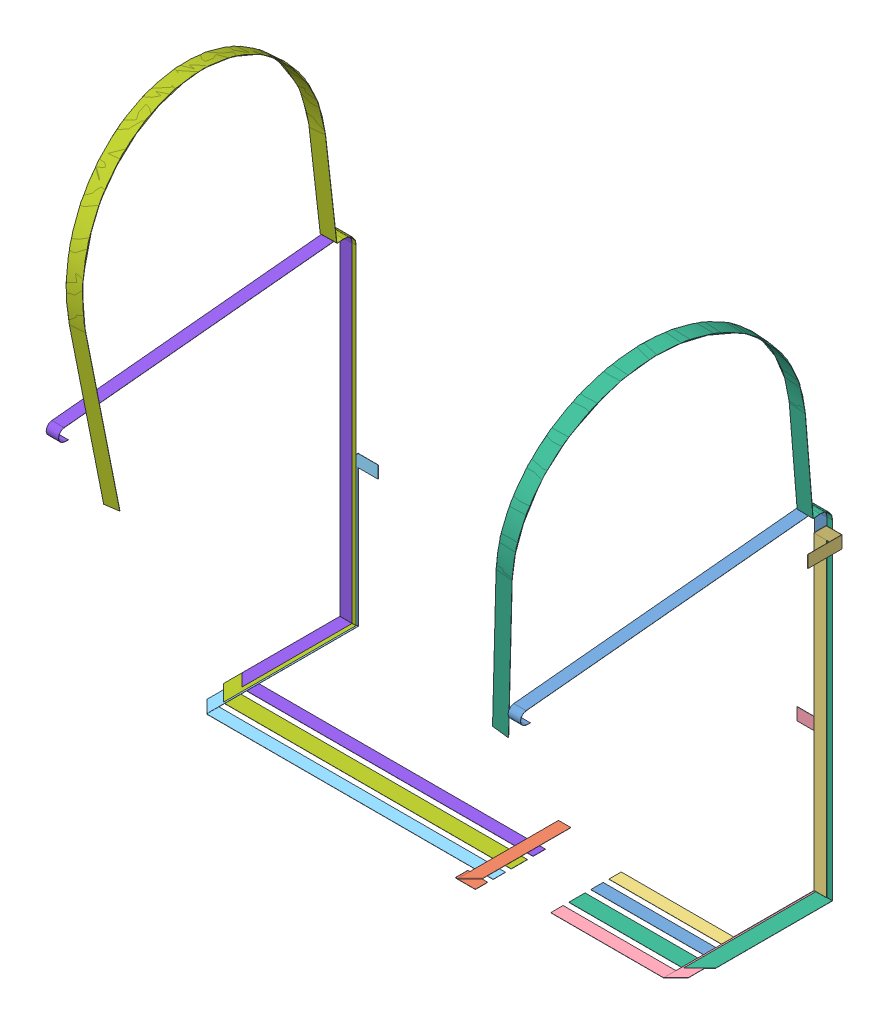
SolidWorks assembly 040M09C00.0P000 Wiring, configuration Default. Lengths in mm.
Overall size (666.76 729.48 399.53).
8 component instances, 8 part files, 52 mates.
Components (placement in the parent):
- 040M09C00.0P01A FFC X1 stepper-1: 040M09C00.0P01A FFC X1 stepper [Right] at (150 -28.8609 147.9733) size (163.25 443.39 398.73)
- 040M09C00.0P03A FFC Z stepper-1: 040M09C00.0P03A FFC Z stepper [Right] at (75 -28.8609 206.9733) x (0 0 1) z (-1 0 0) size (130.9 1.15 26)
- 040M09C00.0P04A FFC Y stepper-1: 040M09C00.0P04A FFC Y stepper [Right] at (150 -28.8609 108.4733) x (0 0 1) z (0 -1 0) size (120.43 183.17 419.7)
- 040M09C00.0P05A FFC Extruder 1-1: 040M09C00.0P05A FFC Extruder 1 [Right] at (150 -28.8609 199.9733) size (163.25 195.95 197.23)
- 040M09C00.0P06B FFC Extruder 0-1: 040M09C00.0P06B FFC Extruder 0 [Left] at (75 -28.8609 199.9733) size (388.25 195.7 197.23)
- 040M09C00.0P08B FFC Hotend 1-1: 040M09C00.0P08B FFC Hotend 1 [Right] at (150 -28.8609 176.4733) size (183.38 729.33 385.22)
- 040M09C00.0P07C FFC Hotend 0-1: 040M09C00.0P07C FFC Hotend 0 [Left] at (75 -28.8609 176.4733) size (408.38 729.48 385.43)
- 040M09C00.0P02B FFC X0 stepper-2: 040M09C00.0P02B FFC X0 stepper [Left] at (75 -28.8609 147.9733) size (395.25 443.39 381.94)
Mates (geometry in assembly coordinates):
- Coincident1: coincident aligned: plane of 040M09C00.0P01A FFC X1 stepper-1 through (150 -29.1109 147.9733) normal (0 -1 0); plane of 040M09C00.0P04A FFC Y stepper-1 through (150 -29.1109 108.4733) normal (0 -1 0)
- Coincident2: coincident aligned: plane of 040M09C00.0P01A FFC X1 stepper-1 through (150 -29.1109 147.9733) normal (0 -1 0); plane of 040M09C00.0P07C FFC Hotend 0-1 through (75 -29.1109 176.4733) normal (0 -1 0)
- Coincident3: coincident aligned: plane of 040M09C00.0P01A FFC X1 stepper-1 through (150 -29.1109 147.9733) normal (0 -1 0); plane of 040M09C00.0P08B FFC Hotend 1-1 through (150 -29.1109 176.4733) normal (0 -1 0)
- Coincident4: coincident aligned: plane of 040M09C00.0P01A FFC X1 stepper-1 through (150 -29.1109 147.9733) normal (0 -1 0); plane of 040M09C00.0P05A FFC Extruder 1-1 through (150 -29.1109 199.9733) normal (0 -1 0)
- Coincident5: coincident aligned: plane of 040M09C00.0P01A FFC X1 stepper-1 through (150 -29.1109 147.9733) normal (0 -1 0); plane of 040M09C00.0P06B FFC Extruder 0-1 through (75 -29.1109 199.9733) normal (0 -1 0)
- Coincident6: coincident aligned: plane of 040M09C00.0P01A FFC X1 stepper-1 through (150 -29.1109 147.9733) normal (0 -1 0); plane of ? through (77.425 3 147.9733) normal (0 -1 0)
- Coincident8: coincident aligned: plane of 040M09C00.0P01A FFC X1 stepper-1 through (150 -29.1109 147.9733) normal (-1 0 0); plane of 040M09C00.0P04A FFC Y stepper-1 through (150 -29.1109 108.4733) normal (-1 0 0)
- Coincident9: coincident aligned: plane of 040M09C00.0P01A FFC X1 stepper-1 through (150 -29.1109 147.9733) normal (-1 0 0); plane of 040M09C00.0P08B FFC Hotend 1-1 through (150 -29.1109 176.4733) normal (-1 0 0)
- Coincident10: coincident aligned: plane of 040M09C00.0P04A FFC Y stepper-1 through (150 -29.1109 108.4733) normal (-1 0 0); plane of 040M09C00.0P05A FFC Extruder 1-1 through (150 -29.1109 199.9733) normal (-1 0 0)
- Coincident11: coincident aligned: plane of 040M09C00.0P06B FFC Extruder 0-1 through (75 -29.1109 199.9733) normal (1 0 0); plane of 040M09C00.0P07C FFC Hotend 0-1 through (75 -29.1109 176.4733) normal (1 0 0)
- Distance2: distance = 75 mm: line of 040M09C00.0P07C FFC Hotend 0-1 through (75 -28.8609 176.4733) axis (0 0 -1); line of 040M09C00.0P08B FFC Hotend 1-1 through (150 -28.8609 155.4733) axis (0 0 1)
- Distance4: distance = 7.5 mm anti-aligned: plane of 040M09C00.0P07C FFC Hotend 0-1 through (-1810 -29.1109 176.4733) normal (0 0 1); plane of 040M09C00.0P06B FFC Extruder 0-1 through (-715 -29.1109 183.9733) normal (0 0 -1)
- Distance5: distance = 7.5 mm anti-aligned: plane of 040M09C00.0P07C FFC Hotend 0-1 through (-1810 -29.1109 155.4733) normal (0 0 -1); plane of ? through (-1268.575 3 147.9733) normal (0 0 1)
- Coincident12: coincident: plane of ? through (77.425 3 147.9733) normal (1 0 0); plane of 040M09C00.0P06B FFC Extruder 0-1 through (75 -29.1109 199.9733) normal (1 0 0)
- Distance6: distance = 7.5 mm anti-aligned: plane of 040M09C00.0P08B FFC Hotend 1-1 through (150 -29.1109 176.4733) normal (0 0 1); plane of 040M09C00.0P05A FFC Extruder 1-1 through (150 -29.1109 183.9733) normal (0 0 -1)
- Distance7: distance = 7.5 mm anti-aligned: plane of 040M09C00.0P08B FFC Hotend 1-1 through (150 -29.1109 155.4733) normal (0 0 -1); plane of 040M09C00.0P01A FFC X1 stepper-1 through (150 -29.1109 147.9733) normal (0 0 1)
- Distance8: distance = 7.5 mm anti-aligned: plane of 040M09C00.0P04A FFC Y stepper-1 through (150 -29.1109 124.4733) normal (0 0 1); plane of 040M09C00.0P01A FFC X1 stepper-1 through (150 -29.1109 131.9733) normal (0 0 -1)
- Coincident20: coincident aligned: plane of 040M09C00.0P07C FFC Hotend 0-1 through (-1810 -29.1109 176.4733) normal (0 0 1); plane of 040M09C00.0P08B FFC Hotend 1-1 through (150 -29.1109 176.4733) normal (0 0 1)
- Distancia1: distance = 3 mm: plane of assembly through (0 0 0) normal (0 0 1); plane of ? through (-286.5 -542.8767 3) normal (0 0 -1)
- Distancia2: distance = 3 mm: plane of ? through (87.5 3 175.6733) normal (0 -1 0); plane of assembly through (0 0 0) normal (0 1 0)
- Distancia3: distance = 307.5 mm: plane of ? through (-307.5 364.6391 857.5836) normal (-1 0 0); plane of assembly through (0 0 0) normal (1 0 0)
- Distancia4: distance = 0.1 mm anti-aligned: plane of 040M09C00.0P02B FFC X0 stepper-2 through (-304 -28.6609 526.9733) normal (0 -1 0); plane of ? through (-286.5 3.7 324.6733) normal (0 1 0)
- Distancia5: distance = 0.1 mm: plane of ? through (-286.5 -317.8767 3.25) normal (0 0 1); plane of 040M09C00.0P02B FFC X0 stepper-2 through (-304 -551.4876 3.8) normal (0 0 -1)
- Coincidente6: coincident: plane of ? through (-137.5 3 175.6733) normal (1 0 0); plane of 040M09C00.0P02B FFC X0 stepper-2 through (75 -29.1109 147.9733) normal (1 0 0)
- Distancia6: distance = 0.1 mm: plane of ? through (-480.5 4.15 543.6733) normal (0 -1 0); plane of 040M09C00.0P02B FFC X0 stepper-2 through (-304 -28.4109 526.9733) normal (0 1 0)
- Distancia7: distance = 0.1 mm anti-aligned: plane of 040M09C00.0P02B FFC X0 stepper-2 through (-304 -551.4876 4.05) normal (0 0 1); plane of ? through (-480.5 -535.4767 3.7) normal (0 0 -1)
- Coincidente9: coincident: plane of ? through (87.5 3.7 200.6733) normal (1 0 0); plane of ? through (87.5 3 175.6733) normal (1 0 0)
- Simétrico1: symmetric: plane of ? through (-300.5 4.4 -217.3267) normal (-1 0 0); plane of ? through (300.5 4.4 347.6733) normal (1 0 0)
- Coincidente10: coincident: plane of ? through (-286.5 -542.8767 3) normal (0 0 -1); plane of ? through (286.5 -317.8767 3) normal (0 0 -1)
- Coincidente11: coincident: plane of ? through (-286.5 3.45 549.6733) normal (0 -1 0); plane of ? through (286.5 3.45 324.6733) normal (0 -1 0)
- Coincidente12: coincident: plane of ? through (87.5 3.7 200.6733) normal (0 -1 0); plane of ? through (137.5 3.7 200.6733) normal (0 -1 0)
- Coincidente13: coincident: plane of ? through (-1048.1267 199.15 4.15) normal (0 0 -1); plane of ? through (823.3767 199.4 4.15) normal (0 0 -1)
- Coincidente14: coincident aligned: plane of 040M09C00.0P02B FFC X0 stepper-2 through (75 -29.1109 147.9733) normal (0 -1 0); plane of ? through (333.5 3.35 147.5233) normal (0 -1 0)
- Coincidente16: coincident aligned: plane of 040M09C00.0P02B FFC X0 stepper-2 through (-1290 -29.1109 131.9733) normal (0 0 -1); plane of ? through (333.5 3.35 131.5233) normal (0 0 -1)
- Distancia8: distance = 0.1 mm: plane of ? through (300 -261.8267 3.7) normal (0 0 -1); plane of ? through (284.5 -287.0267 3.6) normal (0 0 1)
- Distancia9: distance = 0.1 mm: plane of ? through (300 4.5 270.3733) normal (0 -1 0); plane of ? through (284.5 4.4 347.6733) normal (0 1 0)
- Coincidente19: coincident: plane of ? through (137.5 3 175.6733) normal (-1 0 0); plane of ? through (137.5 3.7 200.6733) normal (-1 0 0)
- Coincidente20: coincident: plane of ? through (137.5 3 175.6733) normal (-1 0 0); plane of ? through (137.5 3.35 147.5233) normal (-1 0 0)
- Coincidente21: coincident: plane of ? through (137.5 3.35 147.5233) normal (-1 0 0); plane of ? through (137.5 4.05 107.8733) normal (-1 0 0)
- Distancia10: distance = 0.1 mm: plane of ? through (-284.5 4.4 572.6733) normal (0 1 0); plane of ? through (87.5 4.5 208.1733) normal (0 -1 0)
- Coincidente23: coincident: plane of ? through (87.5 3.7 200.6733) normal (1 0 0); plane of ? through (87.5 4.75 208.1733) normal (1 0 0)
- Distancia11: distance = 23.5 mm: plane of ? through (-702.5 3.7 200.6733) normal (0 0 1); plane of ? through (87.5 4.75 224.1733) normal (0 0 1)
- Distancia12: distance = 3 mm: plane of assembly through (0 0 0) normal (0 1 0); plane of ? through (77.425 3 147.9733) normal (0 -1 0)
- Distancia13: distance = 3 mm anti-aligned: plane of 040M09C00.0P05A FFC Extruder 1-1 through (297 -372.2876 3) normal (0 0 -1); plane of assembly through (0 0 0) normal (0 0 1)
- Simétrico2: symmetric aligned: plane of 040M09C00.0P08B FFC Hotend 1-1 through (320 400.0294 18.8) normal (1 0 0); plane of 040M09C00.0P07C FFC Hotend 0-1 through (-320 400.0294 18.8) normal (-1 0 0); plane of assembly through (0 0 0) normal (1 0 0)
- Coincidente24: coincident: plane of ? through (77.425 3.25 147.9733) normal (0 1 0); plane of 040M09C00.0P03A FFC Z stepper-1 through (75 -28.8609 206.9733) normal (0 -1 0)
- Distancia15: distance = 7 mm anti-aligned: plane of 040M09C00.0P03A FFC Z stepper-1 through (75 -28.6109 206.9733) normal (0 0 -1); plane of 040M09C00.0P06B FFC Extruder 0-1 through (-715 -29.1109 199.9733) normal (0 0 1)
- Coincidente26: coincident aligned: line of 040M09C00.0P07C FFC Hotend 0-1 through (75 -28.8609 176.4733) axis (0 0 -1); line of 040M09C00.0P02B FFC X0 stepper-2 through (75 -28.8609 147.9733) axis (0 0 -1)
- Coincidente27: coincident aligned: plane of 040M09C00.0P07C FFC Hotend 0-1 through (75 -28.8609 176.4733) normal (0 1 0); plane of 040M09C00.0P02B FFC X0 stepper-2 through (75 -28.8609 147.9733) normal (0 1 0)
- Distancia16: distance = 7.5 mm anti-aligned: plane of 040M09C00.0P02B FFC X0 stepper-2 through (-1290 -29.1109 147.9733) normal (0 0 1); plane of 040M09C00.0P07C FFC Hotend 0-1 through (-1810 -29.1109 155.4733) normal (0 0 -1)
- Coincidente29: coincident anti-aligned: plane of 040M09C00.0P03A FFC Z stepper-1 through (75 -28.8609 206.9733) normal (0 -1 0); plane of 040M09C00.0P06B FFC Extruder 0-1 through (75 -28.8609 199.9733) normal (0 1 0)
- Coincidente33: coincident aligned: plane of 040M09C00.0P03A FFC Z stepper-1 through (75 -28.6109 206.9733) normal (1 0 0); plane of 040M09C00.0P06B FFC Extruder 0-1 through (75 -29.1109 199.9733) normal (1 0 0)
